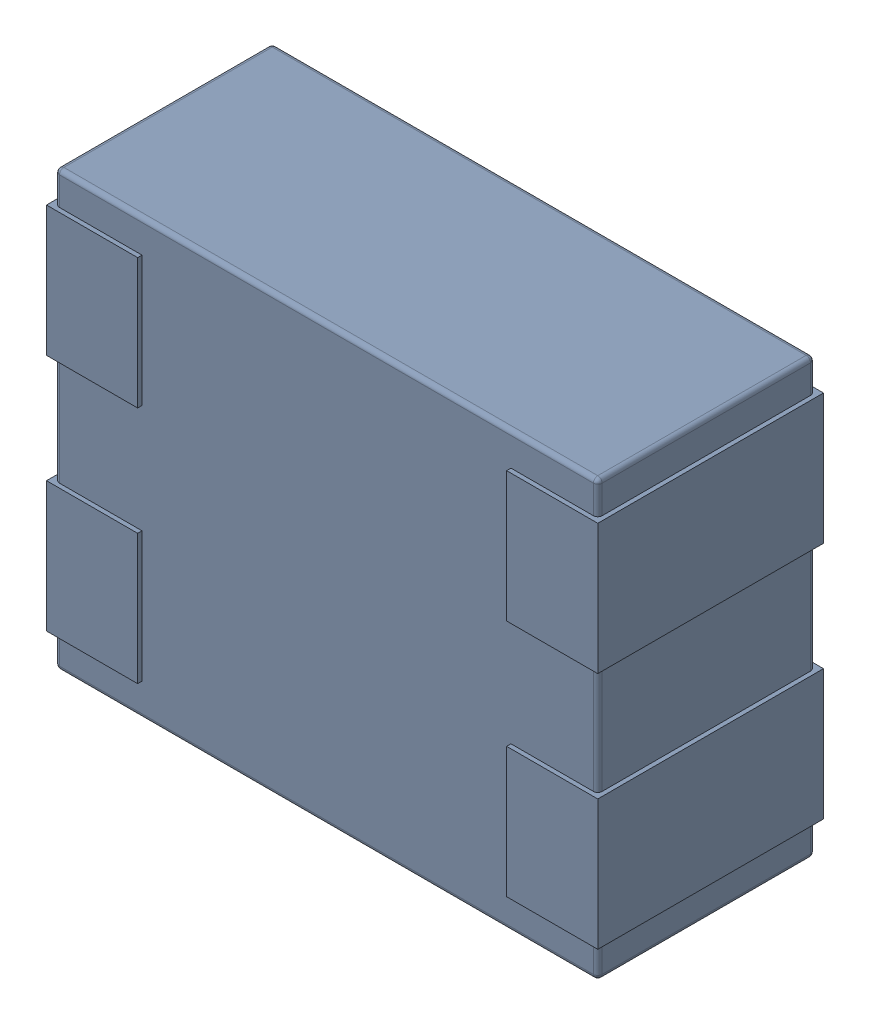
SolidWorks assembly L17, configuration Défaut. Lengths in mm.
Overall size (1.27 1 0.52).
4 component instances, 1 part files, 0 mates.
Components (placement in the parent):
- MCZ1210DH900L2TA0G-1: MCZ1210DH900L2TA0G [Défaut] at (76.7165 -25.9965 -1.6) x (0 -1 0) z (0 0 1) size (1 1.27 0.52)
  - 3D_PCB1_2021-12-30 (1).step-1: 3D_PCB1_2021-12-30 (1).step [Défaut] at origin size (1 1.27 0.52)
    - a3ec64f90eb5404ebd79eca0046a794a.step-1: a3ec64f90eb5404ebd79eca0046a794a.step [Défaut] at (5.0419 -6.8961 1.6) size (1 1.27 0.52)
      - SOLID.step_650-1: SOLID.step_650 [Défaut] at origin size (1 1.27 0.52)
